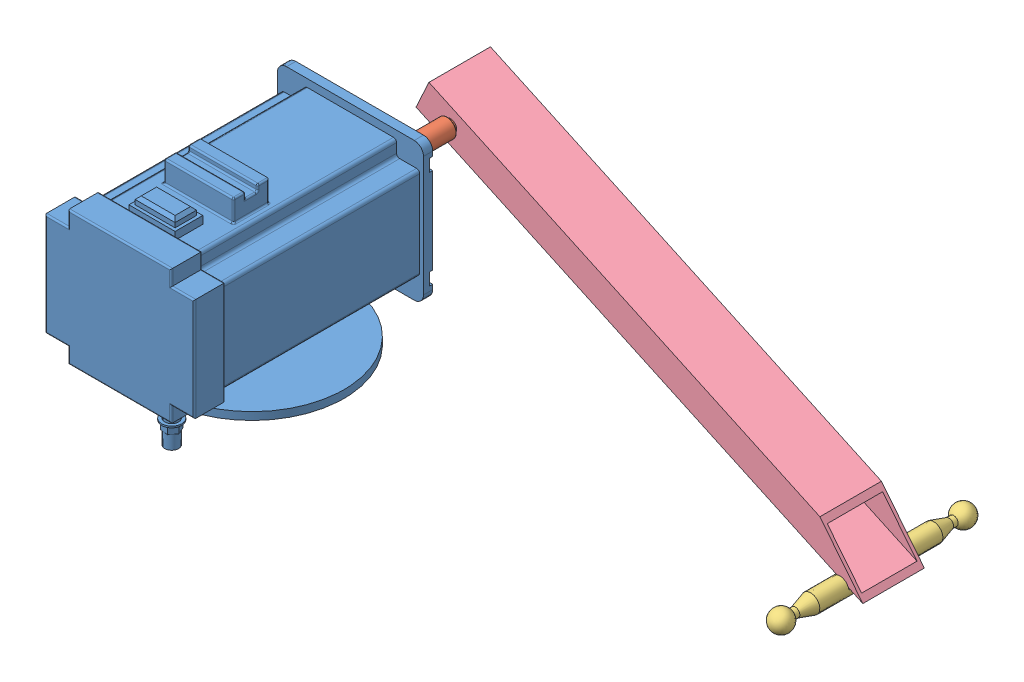
SolidWorks assembly Assem 2, configuration Default. Lengths in mm.
Overall size (1682.51 990.24 1505).
4 component instances, 4 part files, 8 mates.
Components (placement in the parent):
- Base-1: Base [Default] at (198.9227 318.0822 407.2728) size (600 715 780)
- motor shaft-1: motor shaft [Default] at (198.9227 318.0822 392.2728) x (0.787686 0.616077 0) z (0 0 -1) size (60 60 510)
- link 1-1: link 1 [Default] at (1469.6392 -341.0117 -17.7272) x (0 0 1) z (0.419646 0.907688 0) size (660 68.46 68.46)
- part 4-1: part 4 [Default] at (198.9227 318.0822 82.2728) x (-0.907688 0.419646 0) z (0 0 -1) size (1600 150 205)
Mates (geometry in assembly coordinates):
- Coincident2: coincident aligned: circle of Base-1; circle of motor shaft-1
- Concentric1: concentric aligned: cylinder of motor shaft-1 through (198.9227 318.0822 -117.7272) axis (0 0 1) radius 20; cylinder of part 4-1 through (198.9227 318.0822 -117.7272) axis (0 0 1) radius 20.25
- Coincident3: coincident anti-aligned: plane of motor shaft-1 through (198.9227 318.0822 -117.7272) normal (0 0 -1); plane of part 4-1 through (198.9227 318.0822 -117.7272) normal (0 0 1)
- Concentric2: concentric aligned: cylinder of link 1-1 through (1448.6569 -386.3961 32.2728) axis (0.419646 0.907688 0) radius 9; cylinder of part 4-1 through (1454.9515 -372.7808 32.2728) axis (0.419646 0.907688 0) radius 9
- Concentric3: concentric aligned: cylinder of link 1-1 through (1448.6569 -386.3961 -67.7272) axis (0.419646 0.907688 0) radius 9; cylinder of part 4-1 through (1454.9515 -372.7808 -67.7272) axis (0.419646 0.907688 0) radius 9
- Coincident4: coincident anti-aligned: plane of link 1-1 through (1475.9339 -327.3964 -17.7272) normal (0.419646 0.907688 0); plane of part 4-1 through (87.1717 314.6624 -117.7272) normal (-0.419646 -0.907688 0)
- Lock1: lock: unknown of motor shaft-1; unknown of part 4-1
- Lock2: lock: unknown of motor shaft-1; unknown of link 1-1
